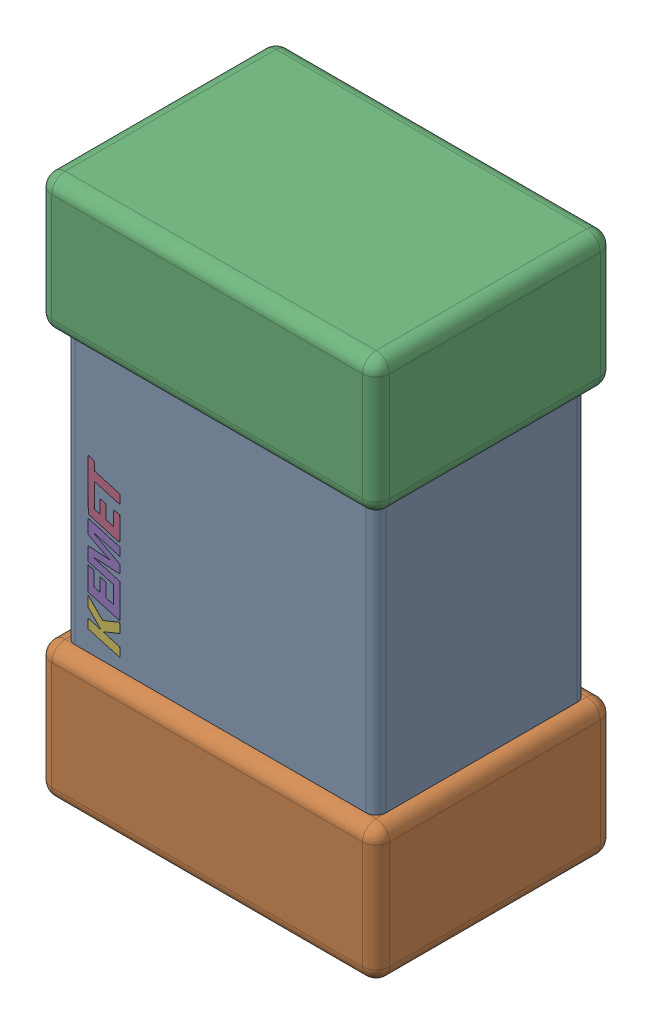
SolidWorks assembly C8.step, configuration Default. Lengths in mm.
Overall size (1.25 2 0.88).
3 component instances, 3 part files, 0 mates.
Components (placement in the parent):
- Cap_KEMET_C0805C472J3HAC_eec.step-1: Cap_KEMET_C0805C472J3HAC_eec.step [Default] at (43.136 65.924 0) x (0 1 0) z (0 0 1) size (1 1.15 0.78)
- Cap_KEMET_C0805C472J3HAC_eec-7.step-1: Cap_KEMET_C0805C472J3HAC_eec-7.step [Default] at (43.136 65.924 0) x (0 1 0) z (0 0 1) size (2 1.25 0.88)
- Cap_KEMET_C0805C472J3HAC_eec-8.step-1: Cap_KEMET_C0805C472J3HAC_eec-8.step [Default] at (43.136 65.924 0) x (0 1 0) z (0 0 1) size (0.59 0.12 0)
